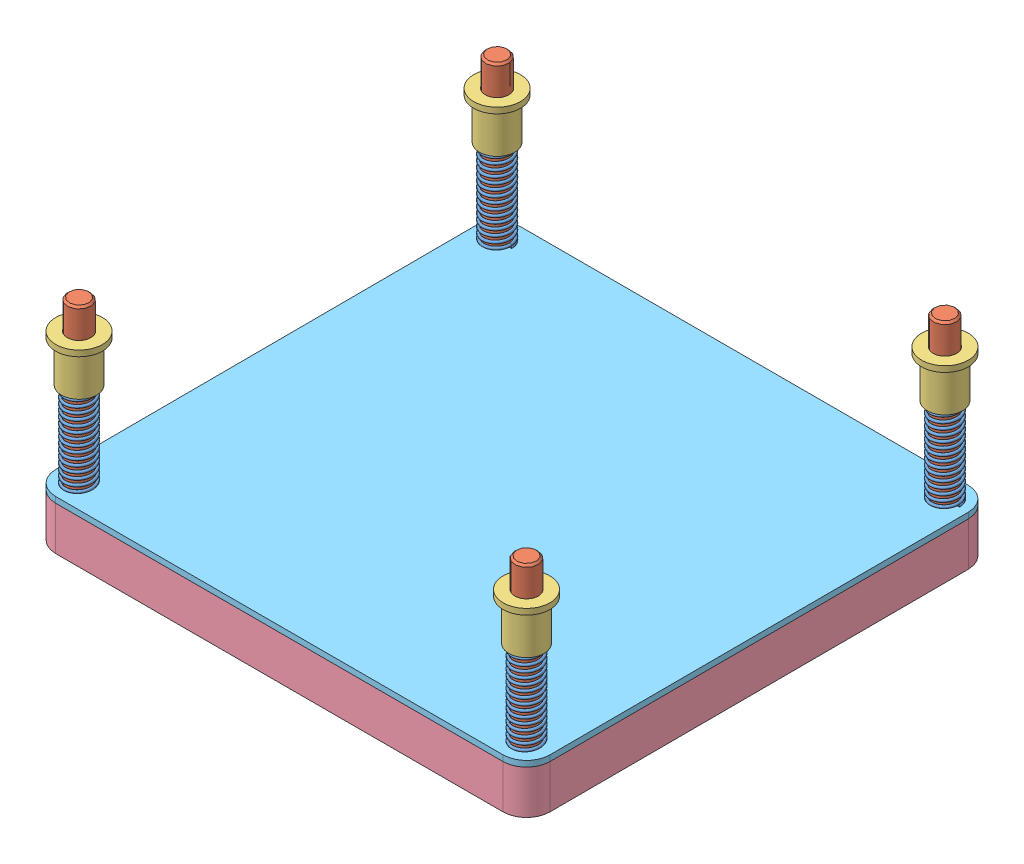
SolidWorks assembly NDE II, configuration Default. Lengths in mm.
Overall size (139.19 57.15 131.52).
14 component instances, 5 part files, 25 mates.
Components (placement in the parent):
- Sensor Springs-1: Sensor Springs [9657K152] at (60.6164 15.0241 -56.7133) x (1 0 0) z (0 -1 0) size (8.76 8.76 25.22)
- Sensor Springs-2: Sensor Springs [9657K152] at (60.8718 13.4366 57.2262) x (1 0 0) z (0 -1 0) size (8.76 8.76 25.22)
- Sensor Springs-3: Sensor Springs [9657K152] at (-60.706 13.4366 57.2262) x (1 0 0) z (0 -1 0) size (8.76 8.76 25.22)
- Sensor Springs-4: Sensor Springs [9657K152] at (-61.0612 15.0241 -56.7133) x (1 0 0) z (0 -1 0) size (8.76 8.76 25.22)
- socket head cap screw_ai-1: socket head cap screw_ai [HX-SHCS 0.25-28x2x1-N] at (-60.706 1.5875 57.2262) x (0 1 0) z (0.087704 0 0.996147) size (57.15 9.53 9.53)
- socket head cap screw_ai-2: socket head cap screw_ai [HX-SHCS 0.25-28x2x1-N] at (60.8718 1.5875 57.2262) x (0 1 0) z (0.087704 0 0.996147) size (57.15 9.53 9.53)
- socket head cap screw_ai-3: socket head cap screw_ai [HX-SHCS 0.25-28x2x1-N] at (-61.0612 1.5875 -56.7133) x (0 1 0) z (0.087704 0 0.996147) size (57.15 9.53 9.53)
- socket head cap screw_ai-4: socket head cap screw_ai [HX-SHCS 0.25-28x2x1-N] at (60.6164 1.5875 -56.7133) x (0 1 0) z (0.087704 0 0.996147) size (57.15 9.53 9.53)
- Bushing-6: Bushing [6338K413] at (-60.706 50.8 57.2262) x (0.992867 0 -0.119228) z (-0.119228 0 -0.992867) size (12.7 12.7 12.7)
- Bushing-8: Bushing [6338K413] at (60.8718 50.8 57.2262) x (0.837169 0 0.546944) z (0.546944 0 -0.837169) size (12.7 12.7 12.7)
- Bushing-5: Bushing [6338K413] at (60.6164 50.8 -56.7133) x (-0.837169 0 -0.546944) z (-0.546944 0 0.837169) size (12.7 12.7 12.7)
- Bushing-7: Bushing [6338K413] at (-61.0612 50.8 -56.7133) x (0.901724 0 0.432313) z (0.432313 0 -0.901724) size (12.7 12.7 12.7)
- Primary Plate^NDE II-1: Primary Plate^NDE II [Default] at (-101.8722 -263.0222 15.1177) size (134.63 11.85 126.64) (virtual)
- Part1^NDE II-1: Part1^NDE II [Default] at (-104.6233 -197.5948 15.4555) size (134.63 1.59 126.64) (virtual)
Mates (geometry in assembly coordinates):
- Coincident33: coincident aligned: plane of Sensor Springs-1 through (64.2168 15.0241 -56.7133) normal (0 0 1); plane of Sensor Springs-4 through (-57.4608 15.0241 -56.7133) normal (0 0 1)
- Coincident34: coincident aligned: plane of Sensor Springs-2 through (64.4723 13.4366 57.2262) normal (0 0 1); plane of Sensor Springs-3 through (-57.1056 13.4366 57.2262) normal (0 0 1)
- Concentric31: concentric aligned: cylinder of Sensor Springs-3 through (-60.706 38.4684 57.2262) axis (0 -1 0) radius 3.3417; cylinder of socket head cap screw_ai-1 through (-60.706 -30.1625 57.2262) axis (0 -1 0) radius 3.175
- Coincident35: coincident aligned: plane of socket head cap screw_ai-1 through (-63.3298 58.7375 57.4572) normal (0 1 0); plane of socket head cap screw_ai-2 through (58.248 58.7375 57.4572) normal (0 1 0)
- Coincident36: coincident: plane of socket head cap screw_ai-2 through (58.248 58.7375 57.4572) normal (0 1 0); plane of socket head cap screw_ai-4 through (57.9926 58.7375 -56.4823) normal (0 1 0)
- Coincident37: coincident: plane of socket head cap screw_ai-3 through (-63.685 58.7375 -56.4823) normal (0 1 0); plane of socket head cap screw_ai-4 through (57.9926 58.7375 -56.4823) normal (0 1 0)
- Concentric33: concentric aligned: cylinder of Sensor Springs-2 through (60.8718 38.4684 57.2262) axis (0 -1 0) radius 3.3417; cylinder of socket head cap screw_ai-2 through (60.8718 -30.1625 57.2262) axis (0 -1 0) radius 3.175
- Concentric34: concentric aligned: cylinder of Sensor Springs-1 through (60.6164 40.0559 -56.7133) axis (0 -1 0) radius 3.3417; cylinder of socket head cap screw_ai-4 through (60.6164 -30.1625 -56.7133) axis (0 -1 0) radius 3.175
- Concentric35: concentric aligned: cylinder of Sensor Springs-4 through (-61.0612 40.0559 -56.7133) axis (0 -1 0) radius 3.3417; cylinder of socket head cap screw_ai-3 through (-61.0612 -30.1625 -56.7133) axis (0 -1 0) radius 3.175
- Concentric36: concentric anti-aligned: cylinder of socket head cap screw_ai-1 through (-60.706 -30.1625 57.2262) axis (0 -1 0) radius 3.175; cylinder of Bushing-1 through (-60.706 38.1 57.2262) axis (0 1 0) radius 3.1877
- Coincident40: coincident anti-aligned: plane of Sensor Springs-3 through (-49.1037 38.1 52.8453) normal (0 1 0); plane of Bushing-1 through (-60.706 38.1 57.2262) normal (0 -1 0)
- Coincident41: coincident aligned: plane of Bushing-1 through (-60.706 50.8 57.2262) normal (0 1 0); plane of Bushing-4 through (-61.0612 50.8 -56.7133) normal (0 1 0)
- Concentric37: concentric anti-aligned: cylinder of socket head cap screw_ai-3 through (-61.0612 -30.1625 -56.7133) axis (0 -1 0) radius 3.175; cylinder of Bushing-4 through (-61.0612 38.1 -56.7133) axis (0 1 0) radius 3.1877
- Concentric38: concentric anti-aligned: cylinder of socket head cap screw_ai-2 through (60.8718 -30.1625 57.2262) axis (0 -1 0) radius 3.175; cylinder of Bushing-2 through (60.8718 38.1 57.2262) axis (0 1 0) radius 4.7879
- Coincident42: coincident anti-aligned: plane of Sensor Springs-2 through (72.4741 38.1 52.8453) normal (0 1 0); plane of Bushing-2 through (60.8718 38.1 57.2262) normal (0 -1 0)
- Coincident43: coincident aligned: plane of Bushing-3 through (60.6164 50.8 -56.7133) normal (0 1 0); plane of Bushing-4 through (-61.0612 50.8 -56.7133) normal (0 1 0)
- Concentric39: concentric anti-aligned: cylinder of socket head cap screw_ai-4 through (60.6164 -30.1625 -56.7133) axis (0 -1 0) radius 3.175; cylinder of Bushing-3 through (60.6164 38.1 -56.7133) axis (0 1 0) radius 4.7879
- Concentric40: concentric aligned: cylinder of Primary Plate^NDE II-1 through (60.8718 198.2706 57.2262) axis (0 -1 0) radius 6.35; cylinder of Part1^NDE II-1 through (60.8718 15.0241 57.2262) axis (0 -1 0) radius 6.35
- Concentric41: concentric aligned: cylinder of Primary Plate^NDE II-1 through (-61.0612 198.2706 -56.7133) axis (0 -1 0) radius 6.35; cylinder of Part1^NDE II-1 through (-61.0612 15.0241 -56.7133) axis (0 -1 0) radius 6.35
- Coincident45: coincident anti-aligned: plane of Primary Plate^NDE II-1 through (71.894 13.4366 52.8453) normal (0 1 0); plane of Part1^NDE II-1 through (60.8718 13.4366 57.2262) normal (0 -1 0)
- Concentric42: concentric anti-aligned: cylinder of Bushing-3 through (60.6164 38.1 -56.7133) axis (0 1 0) radius 4.7879; cylinder of Part1^NDE II-1 through (60.6164 15.0241 -56.7133) axis (0 -1 0) radius 6.35
- Concentric43: concentric anti-aligned: cylinder of Bushing-4 through (-61.0612 38.1 -56.7133) axis (0 1 0) radius 4.7879; cylinder of Part1^NDE II-1 through (-61.0612 15.0241 -56.7133) axis (0 -1 0) radius 6.35
- Coincident51: coincident aligned: plane of Sensor Springs-1 through (72.2187 39.6875 -61.0943) normal (0 1 0); plane of Sensor Springs-4 through (-49.4589 39.6875 -61.0943) normal (0 1 0)
- Coincident52: coincident aligned: plane of Bushing-1 through (-60.706 50.8 57.2262) normal (0 1 0); plane of Bushing-2 through (60.8718 50.8 57.2262) normal (0 1 0)
- Distance1: distance = 7.9375 mm aligned: plane of Bushing-1 through (-60.706 50.8 57.2262) normal (0 1 0); plane of socket head cap screw_ai-1 through (-63.3298 58.7375 57.4572) normal (0 1 0)
